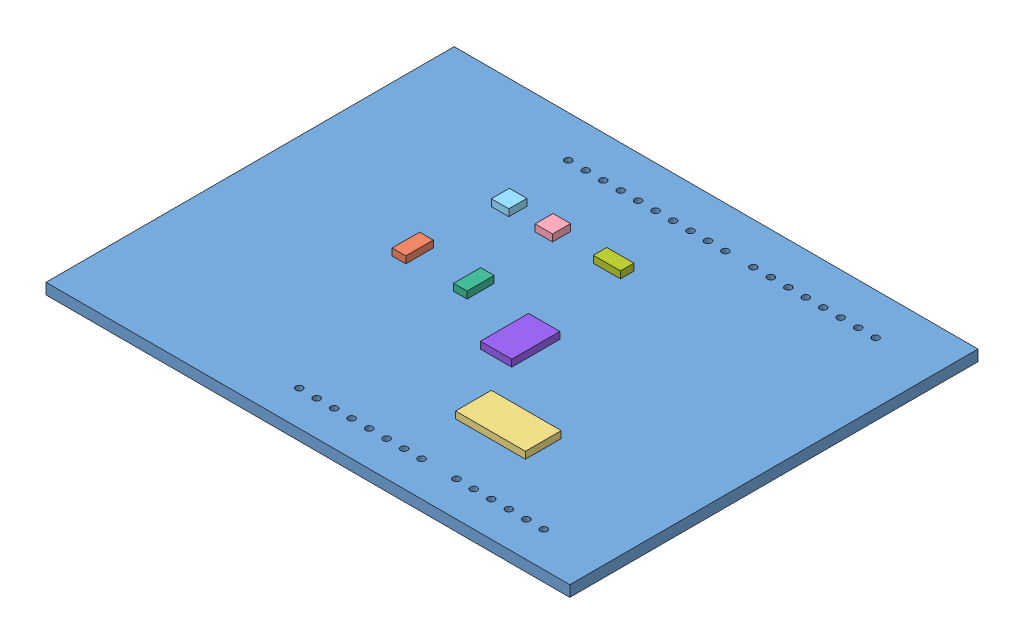
SolidWorks assembly initial_schematic, configuration Default. Lengths in mm.
Overall size (76.18 2.6 59.36).
8 component instances, 8 part files, 0 mates.
Components (placement in the parent):
- initial_schematic-1: initial_schematic [Default] x (1 0 0) z (0 1 0) size (76.18 59.36 1.6)
- C0805_C1_C0805-1: C0805_C1_C0805 [Default] at (57.15 1.6 -41.91) x (0 0 -1) z (0 1 0) size (4 1.99 1)
- AB9V_AB9V-1: AB9V_AB9V [Default] at (86.36 1.6 -26.67) x (0 0 -1) z (0 1 0) size (5.21 10.16 1)
- 1X01_JP1_1X01-1: 1X01_JP1_1X01 [Default] at (64.77 1.6 -54.61) x (1 0 0) z (0 1 0) size (2.54 2.62 1)
- 1X01_JP2_1X01-1: 1X01_JP2_1X01 [Default] at (58.42 1.6 -54.61) x (1 0 0) z (0 1 0) size (2.54 2.62 1)
- R0805W_50000-1: R0805W_50000 [Default] at (66.04 1.6 -41.91) x (0 0 1) z (0 1 0) size (3.95 1.97 1)
- R0805W_200-1: R0805W_200 [Default] at (73.66 1.6 -54.61) x (1 0 0) z (0 1 0) size (3.95 1.97 1)
- BTN_CK_KSS_SW1_BTN_CK_KSS-1: BTN_CK_KSS_SW1_BTN_CK_KSS [Default] at (76.2 1.6 -38.1) x (0 0 -1) z (0 1 0) size (7 4.55 1)
